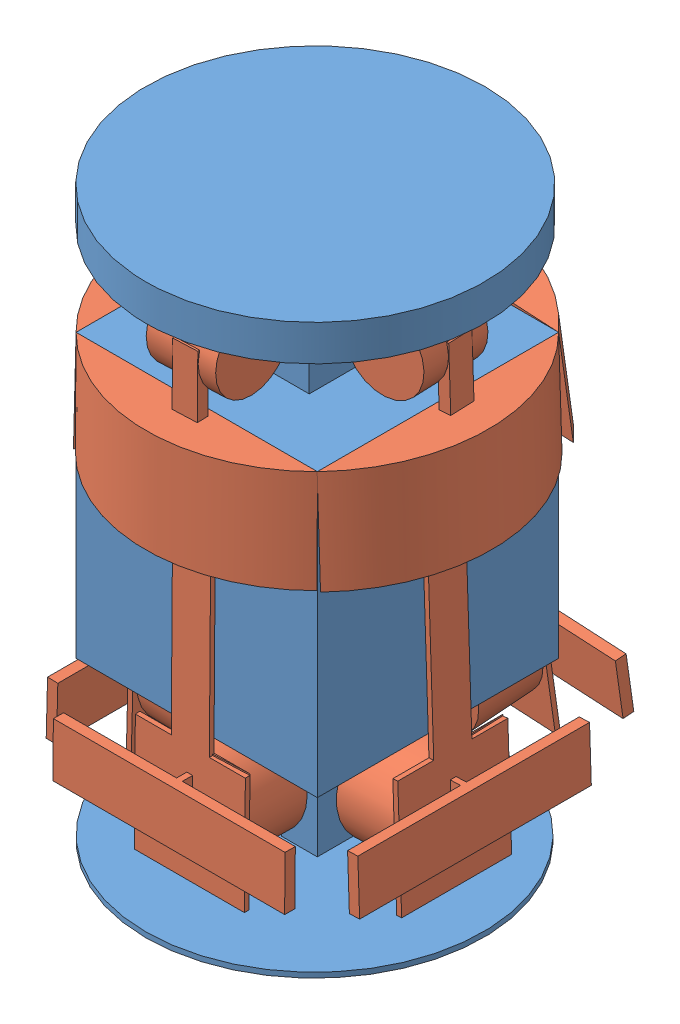
SolidWorks assembly Assem1, configuration Default. Lengths in mm.
Overall size (73.33 111 80.44).
5 component instances, 2 part files, 7 mates.
Components (placement in the parent):
- Part1-1: Part1 [Default] at (13.7374 -0.6868 112.0514) size (66.19 111 66.06)
- Part2-1: Part2 [Default] at (38.2633 63.5592 88.5714) x (0.998606 0.033016 -0.041185) z (0.041162 0.001361 0.999152) size (22.27 97.36 47)
- Part2-2: Part2 [Default] at (37.2574 64.1459 89.0495) x (0.041185 0.007246 0.999125) z (-0.999152 0.000299 0.041184) size (22.27 97.36 47)
- Part2-3: Part2 [Default] at (36.3694 63.7315 88.5315) x (-0.998829 0.025386 0.041185) z (-0.041171 0.001046 -0.999152) size (22.27 97.36 47)
- Part2-6: Part2 [Default] at (36.2149 61.3295 84.0091) x (0.012982 0.132826 -0.991054) z (0.999858 0.00893 0.014294) size (22.27 97.36 47)
Mates (geometry in assembly coordinates):
- Coincident2: coincident anti-aligned: line of Part1-1 through (60.7374 84.3132 112.0514) axis (0 0 -1); line of Part2-1 through (60.7374 84.3132 65.0514) axis (0 0 1)
- Coincident3: coincident: line of Part1-1 through (60.7374 84.3132 65.0514) axis (-1 0 0); point of Part2-1
- Coincident5: coincident anti-aligned: line of Part1-1 through (13.7374 84.3132 112.0514) axis (1 0 0); line of Part2-2 through (60.7773 84.3132 112.0514) axis (-1 0 0)
- Coincident6: coincident: line of Part1-1 through (13.7374 84.3132 65.0514) axis (0 0 1); point of Part2-2
- Coincident14: coincident: point of Part1-1; point of Part2-3
- Coincident17: coincident anti-aligned: line of Part1-1 through (13.7374 84.3132 65.0514) axis (0 0 1); line of Part2-3 through (13.7374 84.3132 112.0514) axis (0 0 -1)
- Coincident34: coincident: point of Part1-1; point of Part2-6
